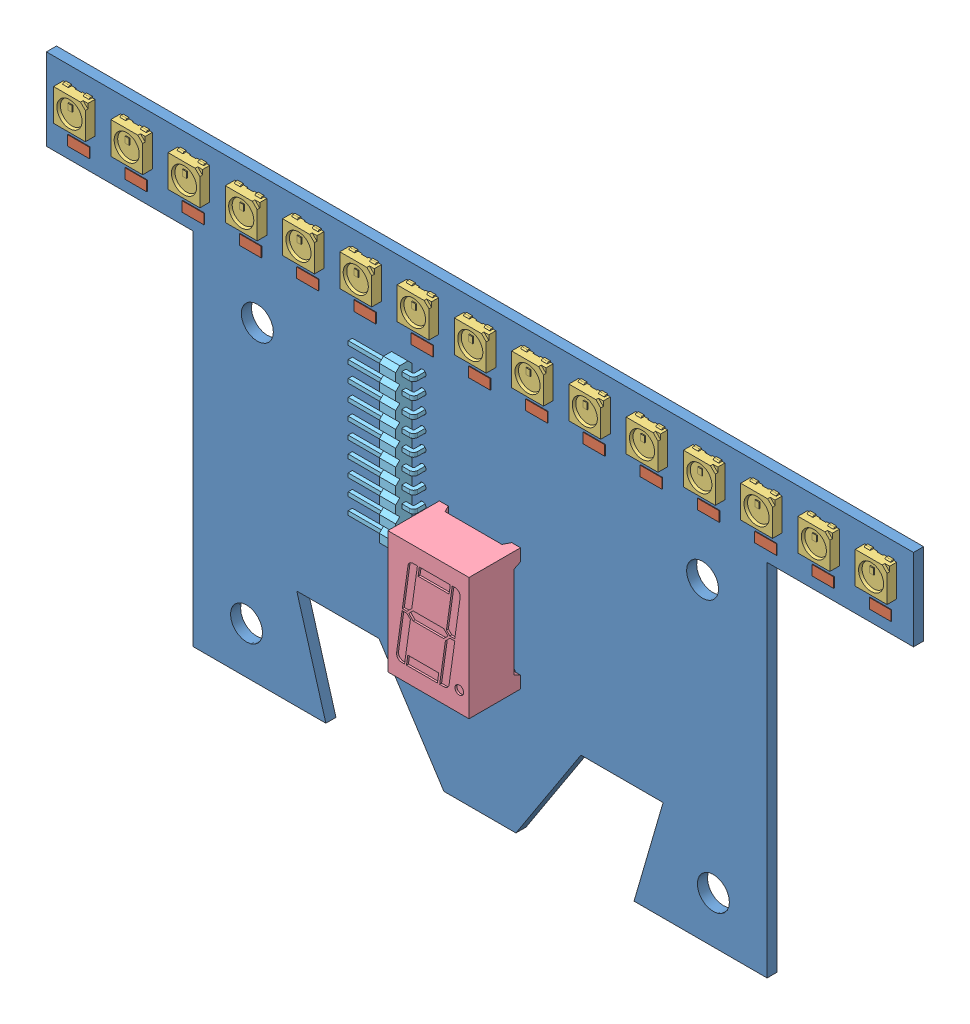
SolidWorks assembly 5_front_9_pcb_new1, configuration Default. Lengths in mm.
Overall size (134.62 68.58 10.87).
34 component instances, 5 part files, 0 mates.
Components (placement in the parent):
- PCB Component_14-1: PCB Component_14 [Default] at origin size (134.62 68.58 10.87)
  - Board_14-1: Board_14 [Default] at origin size (134.62 68.58 1.57)
  - 1005_C12-1: 1005_C12 [Default] at (31.75 58.42 1.57) size (3.38 1.55 0.1)
  - 1005_C12-2: 1005_C12 [Default] at (58.42 58.42 1.57) size (3.38 1.55 0.1)
  - 1005_C12-3: 1005_C12 [Default] at (49.53 58.42 1.57) size (3.38 1.55 0.1)
  - 1005_C12-4: 1005_C12 [Default] at (22.86 58.42 1.57) size (3.38 1.55 0.1)
  - 1005_C12-5: 1005_C12 [Default] at (13.97 58.42 1.57) size (3.38 1.55 0.1)
  - 1005_C12-6: 1005_C12 [Default] at (5.08 58.42 1.57) size (3.38 1.55 0.1)
  - 1005_C12-7: 1005_C12 [Default] at (129.54 58.42 1.57) size (3.38 1.55 0.1)
  - 1005_C12-8: 1005_C12 [Default] at (40.64 58.42 1.57) size (3.38 1.55 0.1)
  - 1005_C12-9: 1005_C12 [Default] at (120.65 58.42 1.57) size (3.38 1.55 0.1)
  - 1005_C12-10: 1005_C12 [Default] at (111.76 58.42 1.57) size (3.38 1.55 0.1)
  - 1005_C12-11: 1005_C12 [Default] at (102.87 58.42 1.57) size (3.38 1.55 0.1)
  - 1005_C12-12: 1005_C12 [Default] at (93.98 58.42 1.57) size (3.38 1.55 0.1)
  - 1005_C12-13: 1005_C12 [Default] at (85.09 58.42 1.57) size (3.38 1.55 0.1)
  - 1005_C12-14: 1005_C12 [Default] at (76.2 58.42 1.57) size (3.38 1.55 0.1)
  - 1005_C12-15: 1005_C12 [Default] at (67.31 58.42 1.57) size (3.38 1.55 0.1)
  - WS2812B_D12-1: WS2812B_D12 [Default] at (129.54 63.5 1.57) x (0 -1 0) z (0 0 1) size (5.35 4.95 1.7)
  - WS2812B_D12-2: WS2812B_D12 [Default] at (120.65 63.5 1.57) x (0 -1 0) z (0 0 1) size (5.35 4.95 1.7)
  - WS2812B_D12-3: WS2812B_D12 [Default] at (111.76 63.5 1.57) x (0 -1 0) z (0 0 1) size (5.35 4.95 1.7)
  - WS2812B_D12-4: WS2812B_D12 [Default] at (102.87 63.5 1.57) x (0 -1 0) z (0 0 1) size (5.35 4.95 1.7)
  - WS2812B_D12-5: WS2812B_D12 [Default] at (93.98 63.5 1.57) x (0 -1 0) z (0 0 1) size (5.35 4.95 1.7)
  - WS2812B_D12-6: WS2812B_D12 [Default] at (85.09 63.5 1.57) x (0 -1 0) z (0 0 1) size (5.35 4.95 1.7)
  - WS2812B_D12-7: WS2812B_D12 [Default] at (76.2 63.5 1.57) x (0 -1 0) z (0 0 1) size (5.35 4.95 1.7)
  - WS2812B_D12-8: WS2812B_D12 [Default] at (67.31 63.5 1.57) x (0 -1 0) z (0 0 1) size (5.35 4.95 1.7)
  - WS2812B_D12-9: WS2812B_D12 [Default] at (58.42 63.5 1.57) x (0 -1 0) z (0 0 1) size (5.35 4.95 1.7)
  - WS2812B_D12-10: WS2812B_D12 [Default] at (49.53 63.5 1.57) x (0 -1 0) z (0 0 1) size (5.35 4.95 1.7)
  - WS2812B_D12-11: WS2812B_D12 [Default] at (40.64 63.5 1.57) x (0 -1 0) z (0 0 1) size (5.35 4.95 1.7)
  - WS2812B_D12-12: WS2812B_D12 [Default] at (31.75 63.5 1.57) x (0 -1 0) z (0 0 1) size (5.35 4.95 1.7)
  - WS2812B_D12-13: WS2812B_D12 [Default] at (22.86 63.5 1.57) x (0 -1 0) z (0 0 1) size (5.35 4.95 1.7)
  - WS2812B_D12-14: WS2812B_D12 [Default] at (13.97 63.5 1.57) x (0 -1 0) z (0 0 1) size (5.35 4.95 1.7)
  - WS2812B_D12-15: WS2812B_D12 [Default] at (5.08 63.5 1.57) x (0 -1 0) z (0 0 1) size (5.35 4.95 1.7)
  - HDSP-M_DIS12-1: HDSP-M_DIS12 [Default] at (67.31 29.21 1.57) size (12.6 19 10.55)
  - 1X10-90_JP12-1: 1X10-90_JP12 [Default] at (54.61 43.18 1.57) x (0 1 0) z (0 0 1) size (25.4 10.36 5.54)
